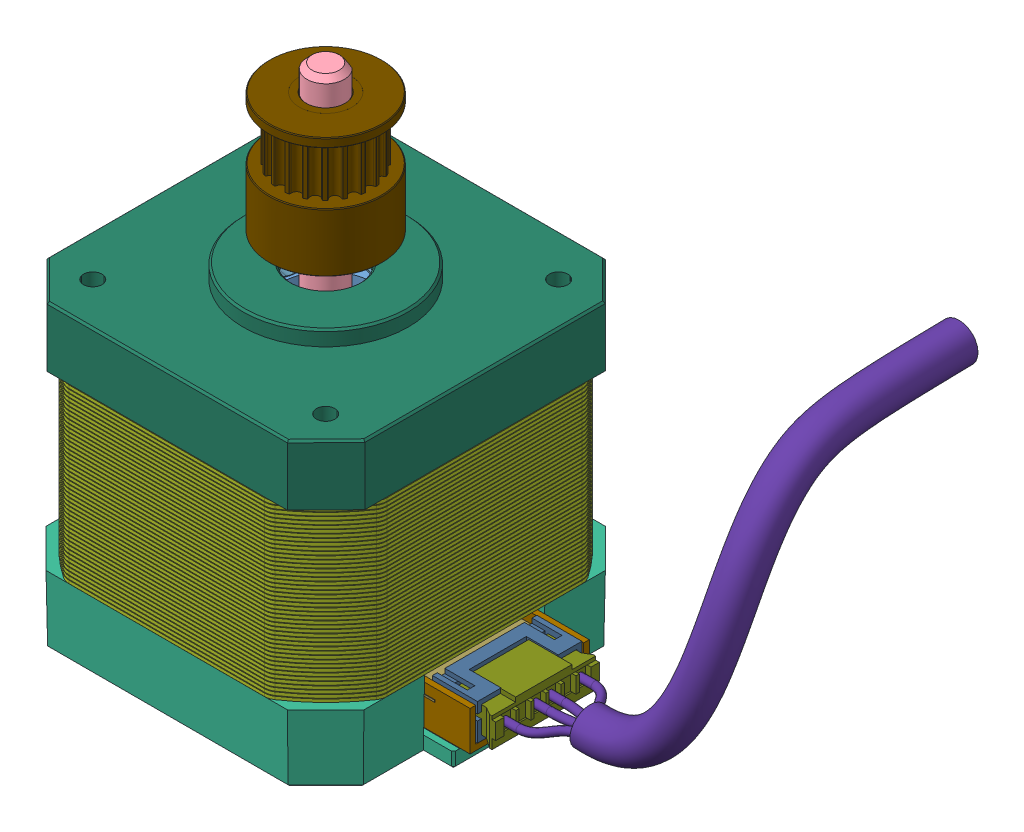
SolidWorks assembly Stepper Assembly, configuration Default. Lengths in mm.
Overall size (76.12 65.73 53.75).
24 component instances, 18 part files, 2 mates.
Components (placement in the parent):
- Nema 17HS4401 Stepper Motor-1: Nema 17HS4401 Stepper Motor [Default] at (0.0135 161.5 -34.9838) size (48.31 65.73 42.31)
  - BS 3469 - 02 - 5 x 16 x 5^Nema 17HS4401 Stepper Motor-1: BS 3469 - 02 - 5 x 16 x 5^Nema 17HS4401 Stepper Motor [Default] at (0.1619 -0.9089 -0.0473) x (0 -1 0) z (0.770185 0 -0.637821) size (5.01 16 16) (virtual)
  - BS 3469 - 02 - 5 x 16 x 5^Nema 17HS4401 Stepper Motor-2: BS 3469 - 02 - 5 x 16 x 5^Nema 17HS4401 Stepper Motor [Default] at (0 -30.75 0) x (0 -1 0) z (-0.000016 0 1) size (5.01 16 16) (virtual)
  - Nema 17 Plastic Spacer 2^Nema 17HS4401 Stepper Motor-1: Nema 17 Plastic Spacer 2^Nema 17HS4401 Stepper Motor [Default] at (-0.0395 -24.15 -0.0395) x (0.999985 0 -0.005516) z (0.005516 0 0.999985) size (9 3 9) (virtual)
  - Nema 17 Plastic Spacer 1-1: Nema 17 Plastic Spacer 1 [Default] at (0 -8.5 0) size (7.75 3 7.75)
  - Nema 17 shaft^Nema 17HS4401 Stepper Motor-1: Nema 17 shaft^Nema 17HS4401 Stepper Motor [Default] at origin size (5 59.5 5) (virtual)
  - ANSI B27.7 - 5, E^Nema 17HS4401 Stepper Motor-1: ANSI B27.7 - 5, E^Nema 17HS4401 Stepper Motor [Default] at (0.0137 -25.65 2.4763) x (0.999985 0 -0.005516) z (0 -1 0) size (8.5 7.05 0.6) (virtual)
  - Nema 17 Base Cap^Nema 17HS4401 Stepper Motor-1: Nema 17 Base Cap^Nema 17HS4401 Stepper Motor [Default] at (0 -37.5 0) x (1 0 0) z (0 0 -1) size (46.16 10 42.31) (virtual)
  - Nema 17 Central Spacer^Nema 17HS4401 Stepper Motor-1: Nema 17 Central Spacer^Nema 17HS4401 Stepper Motor [Default] at (0 -20.5 0) size (42.3 23 42.3) (virtual)
  - Nema 17 Stator Face^Nema 17HS4401 Stepper Motor-1: Nema 17 Stator Face^Nema 17HS4401 Stepper Motor [Default] at (0 -16 0) size (27.8 16 27.8) (virtual)
  - Nema 17 plastic^Nema 17HS4401 Stepper Motor-1: Nema 17 plastic^Nema 17HS4401 Stepper Motor [Default] at (0 -21.8633 0) size (46.3 30.22 38.3) (virtual)
  - S6B-PH-K-S^Nema 17HS4401 Stepper Motor-1: S6B-PH-K-S^Nema 17HS4401 Stepper Motor [Default] at (14.2 -27.906 -11.75) x (0 0 -1) z (1 0 0) size (13.9 8.2 6.5) (virtual)
  - EN ISO 7045 - M3 x 25(1)^Nema 17HS4401 Stepper Motor-1: EN ISO 7045 - M3 x 25(1)^Nema 17HS4401 Stepper Motor [Default] at (15.5 -35.6028 -15.5) x (0 1 0) z (0 0 1) size (27.48 5.6 5.6) (virtual)
  - EN ISO 7045 - M3 x 25(1)^Nema 17HS4401 Stepper Motor-2: EN ISO 7045 - M3 x 25(1)^Nema 17HS4401 Stepper Motor [Default] at (-15.5 -35.6168 15.5) x (0 1 0) z (0 0 1) size (27.48 5.6 5.6) (virtual)
  - EN ISO 7045 - M3 x 25(1)^Nema 17HS4401 Stepper Motor-3: EN ISO 7045 - M3 x 25(1)^Nema 17HS4401 Stepper Motor [Default] at (15.5 -35.5356 15.5) x (0 1 0) z (0 0 1) size (27.48 5.6 5.6) (virtual)
  - EN ISO 7045 - M3 x 25(1)^Nema 17HS4401 Stepper Motor-4: EN ISO 7045 - M3 x 25(1)^Nema 17HS4401 Stepper Motor [Default] at (-15.5 -35.7498 -15.5) x (0 1 0) z (0 0 1) size (27.48 5.6 5.6) (virtual)
  - Nema 17 plastic protector^Nema 17HS4401 Stepper Motor-1: Nema 17 plastic protector^Nema 17HS4401 Stepper Motor [Default] at (0 -31 0) x (0 0 1) z (-1 0 0) size (39 0.25 23) (virtual)
  - Nema 17 PCB^Nema 17HS4401 Stepper Motor-1: Nema 17 PCB^Nema 17HS4401 Stepper Motor [Default] at (-0.719 -35.4655 0.0967) x (0 0 1) z (-1 0 0) size (38 0.8 24.5) (virtual)
  - Nema 17 Sprung Washer^Nema 17HS4401 Stepper Motor-1: Nema 17 Sprung Washer^Nema 17HS4401 Stepper Motor [Default] at (0 -0.3984 0) x (0.985654 0 0.168779) z (-0.168779 0 0.985654) size (15.5 2.12 15.5) (virtual)
  - 17HS4401-Part5^Nema 17HS4401 Stepper Motor-1: 17HS4401-Part5^Nema 17HS4401 Stepper Motor [Default] at (0 2.5 0) x (0 0 1) z (-1 0 0) size (42.3 11 42.3) (virtual)
- CableStepperY^Stepper Assembly-1: CableStepperY^Stepper Assembly [Default] at (26.2469 127.3107 -32.6031) x (0 0 1) z (-1 0 0) size (39.62 41.77 32.16) (virtual)
  - PHR-6-connector-1: PHR-6-connector [Default] at origin size (13.8 4.5 22.35)
  - Part1^CableStepperY_Stepper Assembly-1: Part1^CableStepperY_Stepper Assembly [Default] at (-7.2321 2.9613 -2.725) x (1 0 0) z (0 1 0) size (38.27 26.01 41.77) (virtual)
- 2GT_20T_Toothed_5mmBore-1: 2GT_20T_Toothed_5mmBore [2GT 20Teeth Pulley] at (0.0135 169.6 -34.9838) x (-0.999502 0 -0.031545) z (0.031545 0 -0.999502) size (15.28 16 15.42)
Mates (geometry in assembly coordinates):
- Concentric3: concentric anti-aligned: cylinder of Nema 17HS4401 Stepper Motor-1/Nema 17 shaft^Nema 17HS4401 Stepper Motor-1 through (0.0135 129.5 -34.9838) axis (0 1 0) radius 2.5; cylinder of 2GT_20T_Toothed_5mmBore-1 through (0.0135 185.5 -34.9838) axis (0 -1 0) radius 2.5
- Distance1: distance = 3.6 mm anti-aligned: plane of Nema 17HS4401 Stepper Motor-1/17HS4401-Part5^Nema 17HS4401 Stepper Motor-1 through (0.0135 166 -34.9838) normal (0 1 0); plane of 2GT_20T_Toothed_5mmBore-1 through (7.7349 169.6 -42.2327) normal (0 -1 0)
